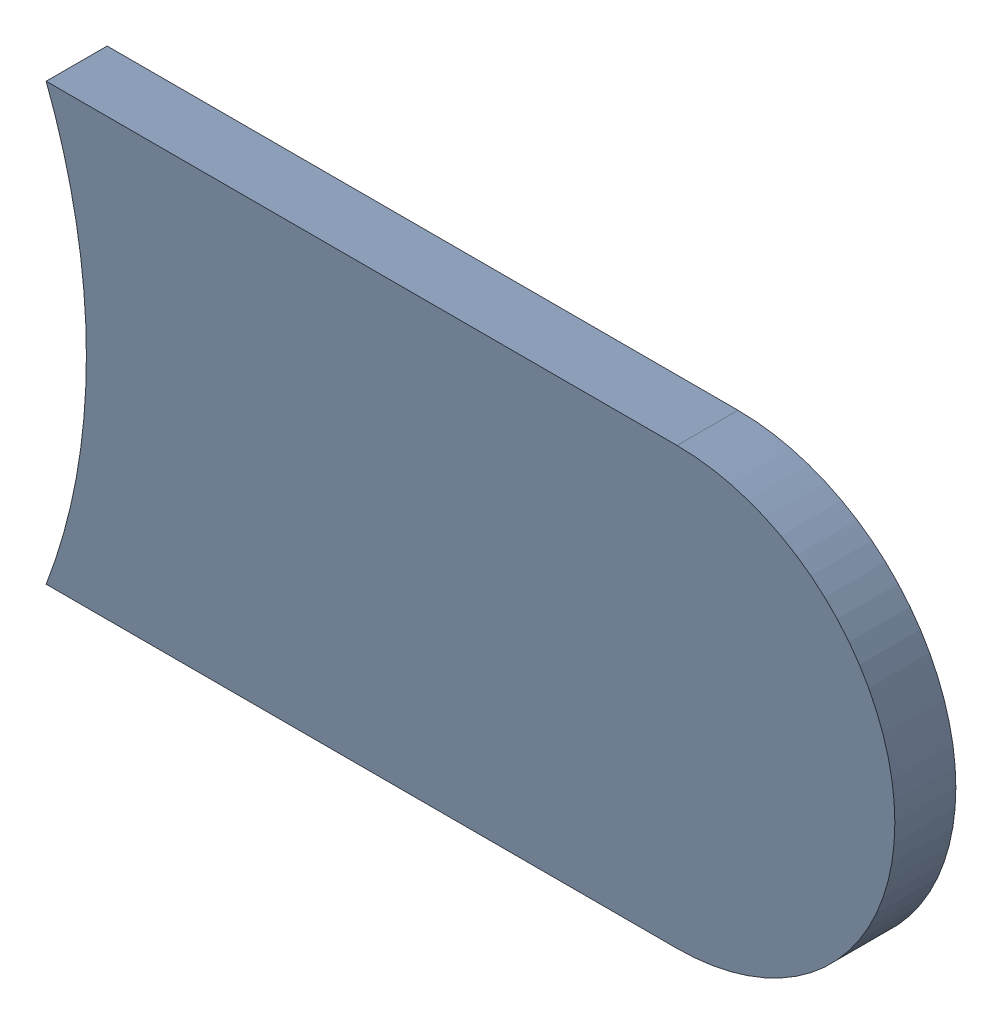
SolidWorks assembly Track (24.4mm,48.5mm)(25.1mm,48.5mm) on Top Layer, configuration Predeterminado. Lengths in mm.
Overall size (0.49 0.25 0.04).
2 component instances, 1 part files, 0 mates.
Components (placement in the parent):
- Track (24.4mm,48.5mm)(25.1mm,48.5mm) on Top Layer-1-1: Track (24.4mm,48.5mm)(25.1mm,48.5mm) on Top Layer-1 [Predeterminado] at (-68.317 -44.187 -0.0457) size (0.49 0.25 0.04)
  - Track (24.4mm,48.5mm)(25.1mm,48.5mm) on Top Layer-Part-1-1: Track (24.4mm,48.5mm)(25.1mm,48.5mm) on Top Layer-Part-1 [Predeterminado] at origin size (0.49 0.25 0.04)
